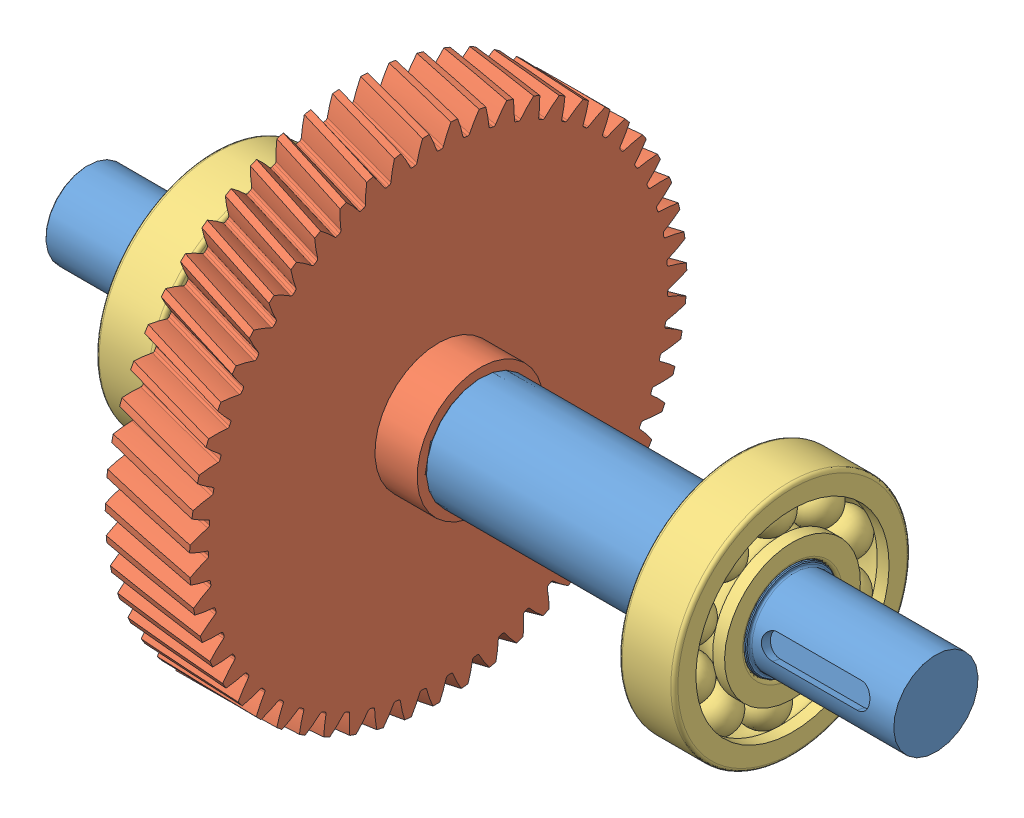
SolidWorks assembly Assem3, configuration Default. Lengths in mm.
Overall size (503 349.2 349.22).
5 component instances, 4 part files, 9 mates.
Components (placement in the parent):
- shaft3-1: shaft3 [Default] at (45.3704 257.3941 391.9838) x (1 0 0) z (0 -0.978527 0.206121) size (503 65 65)
- helical gear_3_am-1: helical gear_3_am [Metric - RH Helical gear 5M 55T 15HA 20PA 50FW ---55O75H75L55.0R1] at (139.6623 257.3941 391.9838) x (-1 0 0) z (0 0.978527 -0.206121) size (75 294.79 294.77)
- radial ball bearing_68_skf-1: radial ball bearing_68_skf [SKF - 6411 - 10,DE,AC,10_68] at (23.1623 257.3941 391.9838) x (1 0 0) z (0 -0.047 0.998895) size (33 140 140)
- radial ball bearing_68_skf-2: radial ball bearing_68_skf [SKF - 6411 - 10,DE,NC,10_68] at (333.1623 257.3941 391.9838) x (1 0 0) z (0 0.028368 0.999598) size (33 140 140)
- bush3-1: bush3 [Default] at (39.6623 257.3941 391.9838) x (0 0 -1) z (1 0 0) size (63 63 50)
Mates (geometry in assembly coordinates):
- Concentric1: concentric anti-aligned: cylinder of shaft3-1 through (224.1898 257.3941 391.9838) axis (1 0 0) radius 27.5; cylinder of helical gear_3_am-1 through (322.8182 257.3941 391.9838) axis (-1 0 0) radius 37.5
- Parallel1: parallel anti-aligned: plane of shaft3-1 through (95.6985 261.8257 413.0222) normal (0 0.206121 0.978527); plane of helical gear_3_am-1 through (204.0682 271.7769 421.452) normal (0 -0.206121 -0.978527)
- Concentric2: concentric aligned: cylinder of shaft3-1 through (224.1898 257.3941 391.9838) axis (1 0 0) radius 27.5; cylinder of radial ball bearing_68_skf-1 through (2.5248 257.3941 391.9838) axis (1 0 0) radius 27.5
- Coincident3: coincident aligned: plane of shaft3-1 through (6.6623 262.5471 416.447) normal (-1 0 0); plane of radial ball bearing_68_skf-1 through (6.6623 297.5996 393.8756) normal (-1 0 0)
- Concentric3: concentric aligned: cylinder of shaft3-1 through (224.1898 257.3941 391.9838) axis (1 0 0) radius 27.5; cylinder of radial ball bearing_68_skf-2 through (312.5248 257.3941 391.9838) axis (1 0 0) radius 27.5
- Coincident4: coincident anti-aligned: plane of shaft3-1 through (316.6623 264.093 423.786) normal (1 0 0); plane of radial ball bearing_68_skf-2 through (316.6623 297.6279 390.842) normal (-1 0 0)
- Coincident5: coincident anti-aligned: plane of radial ball bearing_68_skf-1 through (39.6623 286.9614 393.375) normal (1 0 0); plane of bush3-1 through (39.6623 257.3941 391.9838) normal (-1 0 0)
- Concentric5: concentric anti-aligned: cylinder of shaft3-1 through (224.1898 257.3941 391.9838) axis (1 0 0) radius 27.5; cylinder of bush3-1 through (89.6623 257.3941 391.9838) axis (-1 0 0) radius 27.5
- Coincident6: coincident anti-aligned: plane of helical gear_3_am-1 through (89.6623 257.3941 391.9838) normal (-1 0 0); plane of bush3-1 through (89.6623 257.3941 391.9838) normal (1 0 0)
